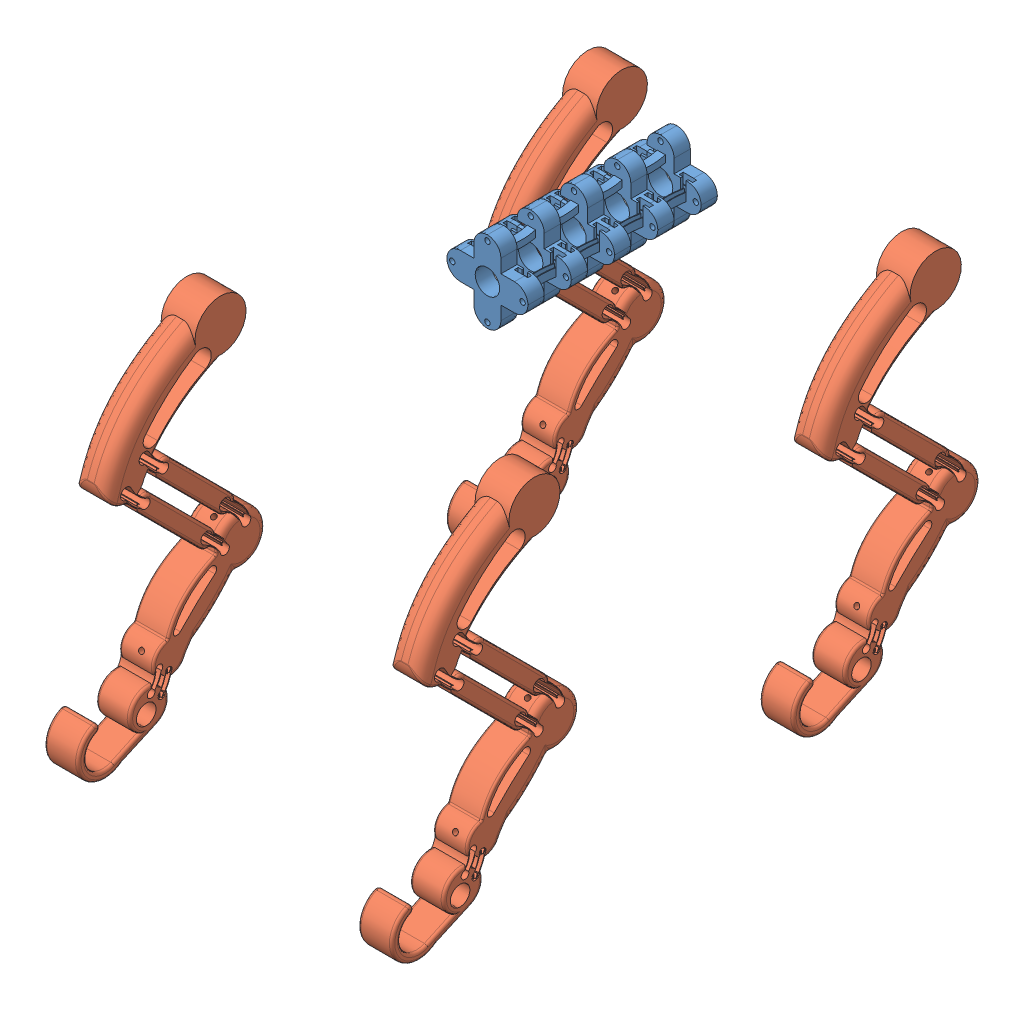
SolidWorks assembly Assem1, configuration Default. Lengths in mm.
Overall size (260.64 320.25 436.09).
6 component instances, 3 part files, 8 mates.
Components (placement in the parent):
- spine_test-1: spine_test [Default] at (51.5813 168.4119 -1.1452) size (60 60 140)
- lock-2: lock [Default] at (-108.5095 138.4119 0.8564) size (61 25 140) (hidden)
- leg_test-1: leg_test [Default] at (-70.0095 57.4901 -30.5836) x (0 0 -1) z (1 0 0) size (139.4 267.16 28.59)
- leg_test-2: leg_test [Default] at (162.0397 57.4901 -30.5836) x (0 0 -1) z (1 0 0) size (139.4 267.16 28.59)
- leg_test-3: leg_test [Default] at (162.0397 61.0753 266.1088) x (0 0 -1) z (1 0 0) size (139.4 267.16 28.59)
- leg_test-4: leg_test [Default] at (-70.0095 61.0753 266.1088) x (0 0 -1) z (1 0 0) size (139.4 267.16 28.59)
Mates (geometry in assembly coordinates):
- Coincident6: coincident anti-aligned: plane of spine_test-1 through (51.5813 158.4119 138.8548) normal (0 -1 0); plane of lock-2 through (-87.5095 158.4119 140.8564) normal (0 1 0)
- Coincident7: coincident anti-aligned: plane of spine_test-1 through (51.5813 158.4119 74.8548) normal (0 -1 0); plane of lock-2 through (-108.5095 158.4119 140.8564) normal (0 1 0)
- Coincident8: coincident anti-aligned: plane of lock-2 through (-82.5095 138.4119 140.8564) normal (1 0 0); plane of leg_test-1 through (-82.5095 10.2555 -72.9927) normal (-1 0 0)
- Parallel1: parallel aligned: plane of leg_test-1 through (-82.5095 10.2555 -72.9927) normal (-1 0 0); plane of leg_test-2 through (149.5397 10.2555 -72.9927) normal (-1 0 0)
- Concentric1: concentric aligned: circle of leg_test-1; circle of leg_test-2
- Coincident12: coincident aligned: plane of leg_test-2 through (174.5397 10.2555 -72.9927) normal (1 0 0); plane of leg_test-3 through (174.5397 13.8406 223.6998) normal (1 0 0)
- Concentric2: concentric aligned: circle of leg_test-3; circle of leg_test-4
- Coincident14: coincident aligned: plane of leg_test-1 through (-82.5095 10.2555 -72.9927) normal (-1 0 0); plane of leg_test-4 through (-82.5095 13.8406 223.6998) normal (-1 0 0)
